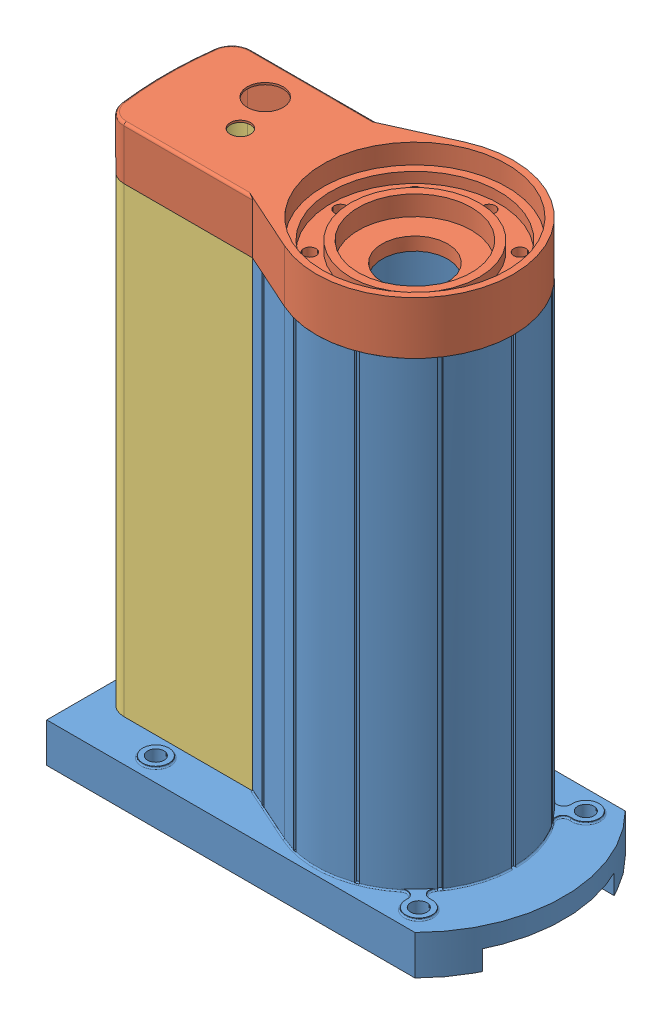
SolidWorks assembly new_DE_2023, configuration Default. Lengths in mm.
Overall size (313.14 421.07 160).
3 component instances, 3 part files, 7 mates.
Components (placement in the parent):
- khau0_base-1: khau0_base [Default] at origin size (313.14 381.07 160)
- khau0_base_connector-1: khau0_base_connector [Default] at (145 381.07 0) size (265 44.5 150)
- khau0_base_support-1: khau0_base_support [Default] at (145 30 0) size (115 351.07 97)
Mates (geometry in assembly coordinates):
- Coincident1: coincident anti-aligned: plane of khau0_base-1 through (133.1099 348.1681 314.8326) normal (-1 0 0); plane of khau0_base_support-1 through (133.1099 -95.3857 334.3326) normal (1 0 0)
- Coincident2: coincident aligned: plane of khau0_base-1 through (208.1099 348.1681 363.3326) normal (0 1 0); plane of khau0_base_support-1 through (35.2771 348.1681 329.8326) normal (0 1 0)
- Coincident3: coincident aligned: line of khau0_base-1 through (133.1099 348.1681 411.8326) axis (0 -1 0); line of khau0_base_support-1 through (133.1099 348.1681 411.8326) axis (0 -1 0)
- Concentric1: concentric aligned: cylinder of khau0_base-1 through (208.1099 -32.9019 363.3326) axis (0 1 0) radius 47.5; cylinder of khau0_base_connector-1 through (208.1099 348.1681 363.3326) axis (0 1 0) radius 25
- Coincident6: coincident anti-aligned: plane of khau0_base_connector-1 through (293.1099 348.1681 410.3326) normal (0 0 1); plane of khau0_base_support-1 through (293.1099 -2.9019 410.3326) normal (0 0 -1)
- Coincident7: coincident anti-aligned: plane of khau0_base-1 through (208.1099 348.1681 363.3326) normal (0 1 0); plane of khau0_base_connector-1 through (35.2771 348.1681 329.8326) normal (0 -1 0)
- Coincident8: coordinate: point of khau0_base-1
